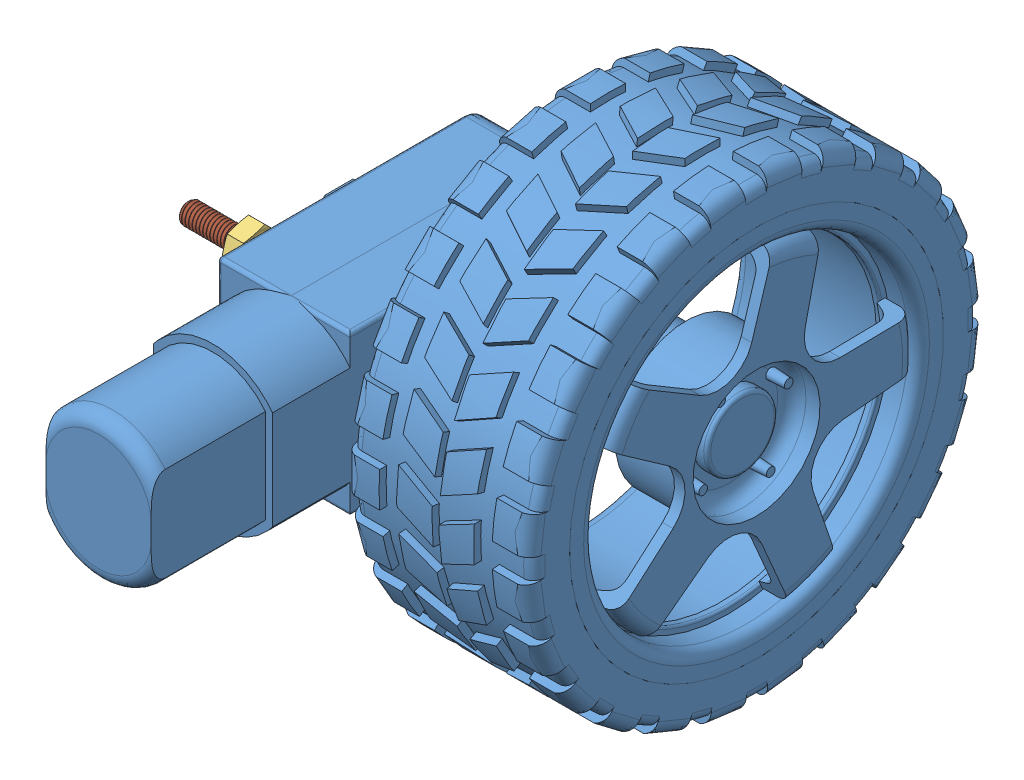
SolidWorks assembly smart_car_motor, configuration Predeterminado. Lengths in mm.
Overall size (60.29 85.1 100.48).
5 component instances, 3 part files, 8 mates.
Components (placement in the parent):
- dc_motor_with_wheel-1: dc_motor_with_wheel [Défaut] at (-4.5268 -19.97 28.6295) x (1 0 0) z (0 0.257157 0.96637) size (59.31 65 86.68)
- (M3_30_mm)_90116A155_METRIC 316 SS PAN HEAD PHILLIPS MACHINE SCREW-1: (M3_30_mm)_90116A155_METRIC 316 SS PAN HEAD PHILLIPS MACHINE SCREW [90116A155] at (-42.5488 -2.5 101.7535) x (0 0 -1) z (1 0 0) size (6 6 32.68)
- (M3_30_mm)_90116A155_METRIC 316 SS PAN HEAD PHILLIPS MACHINE SCREW-2: (M3_30_mm)_90116A155_METRIC 316 SS PAN HEAD PHILLIPS MACHINE SCREW [90116A155] at (-42.5488 -20 101.7535) x (0 0 -1) z (1 0 0) size (6 6 32.68)
- M3 Nut-1: M3 Nut [Predeterminado] at (-30.8488 -2.5 101.7535) x (0 -0.257157 -0.96637) z (1 0 0) size (6.27 6.27 2.71)
- M3 Nut-2: M3 Nut [Predeterminado] at (-30.8488 -20 101.7535) x (0 -0.257157 -0.96637) z (1 0 0) size (6.27 6.27 2.71)
Mates (geometry in assembly coordinates):
- Concéntrica1: concentric: circle of dc_motor_with_wheel-1; circle of (M3_30_mm)_90116A155_METRIC 316 SS PAN HEAD PHILLIPS MACHINE SCREW-1
- Coincidente4: coincident: plane of dc_motor_with_wheel-1 through (-32.3488 -11.25 81.1535) normal (-1 0 0); plane of M3 Nut-2 through (-32.3488 -20 101.7535) normal (1 0 0)
- Concéntrica3: concentric: circle of dc_motor_with_wheel-1; circle of M3 Nut-2
- Coincidente3: coincident: plane of dc_motor_with_wheel-1 through (-32.3488 -11.25 81.1535) normal (-1 0 0); plane of M3 Nut-1 through (-32.3488 -2.5 101.7535) normal (1 0 0)
- Concéntrica4: concentric: circle of dc_motor_with_wheel-1; circle of M3 Nut-1
- Coincident1: coincident: plane of dc_motor_with_wheel-1 through (-13.5488 0 69.9535) normal (0 1 0); plane of assembly
- Concentric1: concentric: circle of (M3_30_mm)_90116A155_METRIC 316 SS PAN HEAD PHILLIPS MACHINE SCREW-2; circle of M3 Nut-2
- Distance1: distance = 1 mm: plane of (M3_30_mm)_90116A155_METRIC 316 SS PAN HEAD PHILLIPS MACHINE SCREW-2 through (-12.5488 -20 101.7535) normal (-1 0 0); plane of dc_motor_with_wheel-1 through (-13.5488 -11.25 81.1535) normal (1 0 0)
